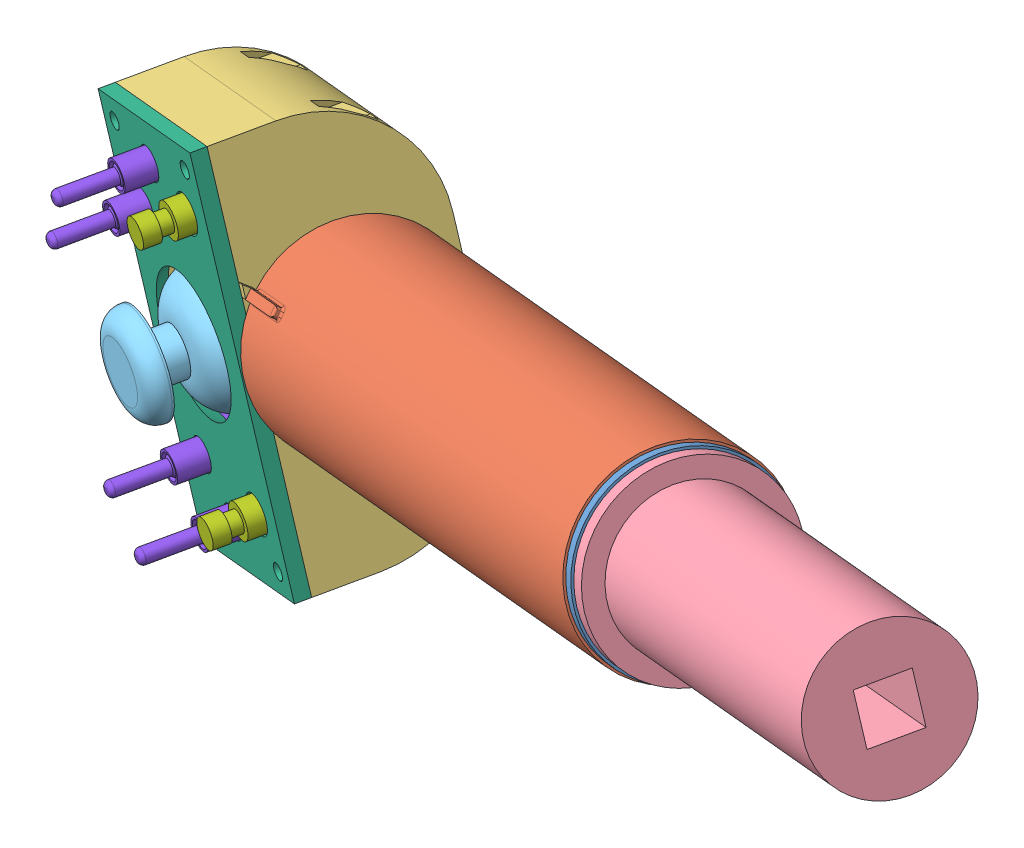
SolidWorks assembly simple_collective_body, configuration По умолчанию. Lengths in mm.
Overall size (251.38 127.81 120.21).
12 component instances, 8 part files, 32 mates.
Components (placement in the parent):
- simple_collective_throttle_frame_part1_slbody02-1: simple_collective_throttle_frame_part1_slbody02 [По умолчанию] at (-143.9465 367.1598 155.02) x (0.322697 0.099734 -0.941233) z (0.295284 -0.95541 0) size (39 92 39)
- simple_collective_throttle_grip_slbody04-1: simple_collective_throttle_grip_slbody04 [По умолчанию] at (-94.487 382.4459 173.5966) x (-0.221382 -0.376779 0.89946) z (-0.899263 -0.277931 -0.337757) size (40 40 126.4)
- simple_collective_throttle_frame_part2_slbody03a-1: simple_collective_throttle_frame_part2_slbody03a [По умолчанию] at (-157.4354 362.9908 149.9536) x (0.295284 -0.95541 0) z (-0.899263 -0.277931 -0.337757) size (78 41.6 93)
- simple_lever_body_decorative_casing_slbody01-2: simple_lever_body_decorative_casing_slbody01 [По умолчанию] at (-20.7474 405.2363 201.2927) x (0.322697 0.099734 -0.941233) z (-0.295284 0.95541 0) size (38 80 38)
- KY-083-2: KY-083 [По умолчанию] at (-223.9465 342.4345 123.3789) x (0.899263 0.277931 0.337757) z (0.295284 -0.95541 0) size (27.6 34.3 38.4)
- compact_collective_switchbox_cover_slbody05-1: compact_collective_switchbox_cover_slbody05 [По умолчанию] at (-230.366 340.4505 140.6228) x (-0.295284 0.95541 0) z (0.899263 0.277931 0.337757) size (78 3 37.5)
- PBS10-B2-1: PBS10-B2 [По умолчанию] at (-226.4692 368.8683 136.4705) x (0.884331 0.322697 0.337381) z (0.337381 -0.941233 0.015935) size (9.4 20 9.4)
- MTS-103-1: MTS-103 [По умолчанию] at (-238.2527 370.4598 131.0056) x (0.899263 0.277931 0.337757) z (0.295284 -0.95541 0) size (13.2 33.3 7.9)
- MTS-103-4: MTS-103 [По умолчанию] at (-219.9452 311.2244 131.0056) x (0.899263 0.277931 0.337757) z (0.295284 -0.95541 0) size (13.2 33.3 7.9)
- MTS-103-5: MTS-103 [По умолчанию] at (-229.0452 318.3553 128.6413) x (0.899263 0.277931 0.337757) z (0.295284 -0.95541 0) size (13.2 33.3 7.9)
- MTS-103-6: MTS-103 [По умолчанию] at (-241.7424 359.4379 128.6413) x (0.899263 0.277931 0.337757) z (0.295284 -0.95541 0) size (13.2 33.3 7.9)
- PBS10-B2-2: PBS10-B2 [По умолчанию] at (-211.1145 319.187 136.4705) x (0.884331 0.322697 0.337381) z (0.337381 -0.941233 0.015935) size (9.4 20 9.4)
Mates (geometry in assembly coordinates):
- Coincident58: coincident anti-aligned: plane of simple_collective_throttle_frame_part1_slbody02-1 through (-94.487 382.4459 173.5966) normal (-0.899263 -0.277931 -0.337757); plane of simple_collective_throttle_grip_slbody04-1 through (-94.487 382.4459 173.5966) normal (0.899263 0.277931 0.337757)
- Concentric21: concentric anti-aligned: cylinder of simple_collective_throttle_frame_part1_slbody02-1 through (-94.487 382.4459 173.5966) axis (-0.899263 -0.277931 -0.337757) radius 18; cylinder of simple_collective_throttle_grip_slbody04-1 through (-208.1539 347.3155 130.9041) axis (0.899263 0.277931 0.337757) radius 18.5
- Concentric27: concentric anti-aligned: cylinder of simple_collective_throttle_frame_part1_slbody02-1 through (-94.487 382.4459 173.5966) axis (-0.899263 -0.277931 -0.337757) radius 18; cylinder of simple_collective_throttle_frame_part2_slbody03a-1 through (-208.6935 347.1487 130.7015) axis (0.899263 0.277931 0.337757) radius 18
- Parallel4: parallel anti-aligned: plane of simple_collective_throttle_frame_part1_slbody02-1 through (-169.3547 355.5106 128.6293) normal (0.322697 0.099734 -0.941233); plane of simple_collective_throttle_frame_part2_slbody03a-1 through (-172.3663 364.18 128.3294) normal (-0.322697 -0.099734 0.941233)
- Coincident60: coincident anti-aligned: plane of simple_collective_throttle_frame_part1_slbody02-1 through (-157.4354 362.9908 149.9536) normal (-0.899263 -0.277931 -0.337757); plane of simple_collective_throttle_frame_part2_slbody03a-1 through (-157.4354 362.9908 149.9536) normal (0.899263 0.277931 0.337757)
- Concentric28: concentric anti-aligned: cylinder of simple_collective_throttle_frame_part1_slbody02-1 through (-92.6885 383.0018 174.2722) axis (-0.899263 -0.277931 -0.337757) radius 19.5; cylinder of simple_lever_body_decorative_casing_slbody01-2 through (-92.6885 383.0018 174.2722) axis (0.899263 0.277931 0.337757) radius 15
- Parallel5: parallel aligned: plane of simple_collective_throttle_frame_part1_slbody02-1 through (-131.8262 376.2699 165.5857) normal (0.295284 -0.95541 0); plane of simple_lever_body_decorative_casing_slbody01-2 through (-92.5473 388.4358 169.4248) normal (0.295284 -0.95541 0)
- Coincident62: coincident anti-aligned: plane of simple_collective_throttle_frame_part1_slbody02-1 through (-92.6885 383.0018 174.2722) normal (0.899263 0.277931 0.337757); plane of simple_lever_body_decorative_casing_slbody01-2 through (-92.6885 383.0018 174.2722) normal (-0.899263 -0.277931 -0.337757)
- Coincident66: coincident anti-aligned: plane of simple_collective_throttle_frame_part2_slbody03a-1 through (-235.0367 298.1868 134.5432) normal (-0.322697 -0.099734 0.941233); plane of compact_collective_switchbox_cover_slbody05-1 through (-230.366 340.4505 140.6228) normal (0.322697 0.099734 -0.941233)
- Coincident67: coincident aligned: plane of simple_collective_throttle_frame_part2_slbody03a-1 through (-208.6935 347.1487 130.7015) normal (0.899263 0.277931 0.337757); plane of compact_collective_switchbox_cover_slbody05-1 through (-226.6635 382.415 149.5261) normal (0.899263 0.277931 0.337757)
- Coincident68: coincident aligned: plane of simple_collective_throttle_frame_part2_slbody03a-1 through (-258.0688 372.7087 134.5432) normal (-0.295284 0.95541 0); plane of compact_collective_switchbox_cover_slbody05-1 through (-226.6635 382.415 149.5261) normal (-0.295284 0.95541 0)
- Parallel10: parallel anti-aligned: plane of simple_collective_throttle_frame_part2_slbody03a-1 through (-196.1147 313.3562 27.3146) normal (0.899263 0.277931 0.337757); plane of KY-083-2 through (-232.1351 322.372 122.1641) normal (-0.899263 -0.277931 -0.337757)
- Distance2: distance = 15 mm anti-aligned: plane of KY-083-2 through (-225.076 342.0855 126.6732) normal (-0.322697 -0.099734 0.941233); plane of compact_collective_switchbox_cover_slbody05-1 through (-230.366 340.4505 140.6228) normal (0.322697 0.099734 -0.941233)
- Concentric38: concentric anti-aligned: cylinder of simple_collective_throttle_frame_part2_slbody03a-1 through (-213.5155 361.2015 108.4386) axis (-0.322697 -0.099734 0.941233) radius 1.5; cylinder of KY-083-2 through (-230.8123 355.8556 158.8897) axis (0.322697 0.099734 -0.941233) radius 1.45
- Concentric39: concentric anti-aligned: cylinder of simple_collective_throttle_frame_part2_slbody03a-1 through (-224.273 330.6633 101.5146) axis (-0.322697 -0.099734 0.941233) radius 1.5; cylinder of KY-083-2 through (-241.5699 325.3174 151.9657) axis (0.322697 0.099734 -0.941233) radius 1.45
- Concentric40: concentric anti-aligned: cylinder of compact_collective_switchbox_cover_slbody05-1 through (-230.0189 367.7713 146.8241) axis (0.322697 0.099734 -0.941233) radius 3.75; cylinder of PBS10-B2-1 through (-229.0508 368.0705 144.0004) axis (-0.322697 -0.099734 0.941233) radius 3.4
- Coincident81: coincident anti-aligned: plane of compact_collective_switchbox_cover_slbody05-1 through (-230.366 340.4505 140.6228) normal (0.322697 0.099734 -0.941233); plane of PBS10-B2-1 through (-229.0508 368.0705 144.0004) normal (-0.322697 -0.099734 0.941233)
- Coincident93: coincident aligned: plane of simple_collective_throttle_grip_slbody04-1 through (-207.6279 361.1244 150.7085) normal (0.018775 -0.795994 0.605013); plane of simple_collective_throttle_frame_part2_slbody03a-1 through (-216.197 357.6854 146.45) normal (0.018775 -0.795994 0.605013)
- Coincident97: coincident anti-aligned: plane of compact_collective_switchbox_cover_slbody05-1 through (-230.366 340.4505 140.6228) normal (0.322697 0.099734 -0.941233); plane of MTS-103-4 through (-223.0108 310.2769 139.9473) normal (-0.322697 -0.099734 0.941233)
- Coincident100: coincident anti-aligned: plane of compact_collective_switchbox_cover_slbody05-1 through (-230.366 340.4505 140.6228) normal (0.322697 0.099734 -0.941233); plane of MTS-103-1 through (-241.3184 369.5123 139.9473) normal (-0.322697 -0.099734 0.941233)
- Parallel18: parallel: line of compact_collective_switchbox_cover_slbody05-1 through (-235.0367 298.1868 134.5432) axis (0.899263 0.277931 0.337757); plane of MTS-103-4 through (-215.9093 308.3374 142.1765) normal (0.295284 -0.95541 0)
- Parallel20: parallel aligned: plane of compact_collective_switchbox_cover_slbody05-1 through (-226.6635 382.415 149.5261) normal (-0.295284 0.95541 0); plane of MTS-103-1 through (-236.5496 375.1205 142.1765) normal (-0.295284 0.95541 0)
- Concentric43: concentric aligned: cylinder of compact_collective_switchbox_cover_slbody05-1 through (-223.9789 309.9777 142.771) axis (0.322697 0.099734 -0.941233) radius 3.2; cylinder of MTS-103-4 through (-225.8505 309.3993 148.2301) axis (0.322697 0.099734 -0.941233) radius 3
- Concentric44: concentric aligned: cylinder of compact_collective_switchbox_cover_slbody05-1 through (-242.2864 369.2131 142.771) axis (0.322697 0.099734 -0.941233) radius 3.2; cylinder of MTS-103-1 through (-244.1581 368.6347 148.2301) axis (0.322697 0.099734 -0.941233) radius 3
- Concentric45: concentric aligned: cylinder of compact_collective_switchbox_cover_slbody05-1 through (-233.0789 317.1086 140.4067) axis (0.322697 0.099734 -0.941233) radius 3.2; cylinder of MTS-103-5 through (-234.9505 316.5302 145.8658) axis (0.322697 0.099734 -0.941233) radius 3
- Concentric46: concentric aligned: cylinder of compact_collective_switchbox_cover_slbody05-1 through (-245.7761 358.1912 140.4067) axis (0.322697 0.099734 -0.941233) radius 3.2; cylinder of MTS-103-6 through (-247.6477 357.6128 145.8658) axis (0.322697 0.099734 -0.941233) radius 3
- Coincident101: coincident anti-aligned: plane of compact_collective_switchbox_cover_slbody05-1 through (-230.366 340.4505 140.6228) normal (0.322697 0.099734 -0.941233); plane of MTS-103-5 through (-232.1108 317.4078 137.583) normal (-0.322697 -0.099734 0.941233)
- Coincident102: coincident anti-aligned: plane of compact_collective_switchbox_cover_slbody05-1 through (-230.366 340.4505 140.6228) normal (0.322697 0.099734 -0.941233); plane of MTS-103-6 through (-244.808 358.4904 137.583) normal (-0.322697 -0.099734 0.941233)
- Parallel21: parallel anti-aligned: plane of MTS-103-4 through (-218.242 315.8851 142.1765) normal (-0.295284 0.95541 0); plane of MTS-103-5 through (-225.0093 315.4683 139.8122) normal (0.295284 -0.95541 0)
- Parallel22: parallel anti-aligned: plane of MTS-103-1 through (-234.2169 367.5728 142.1765) normal (0.295284 -0.95541 0); plane of MTS-103-6 through (-240.0392 364.0986 139.8122) normal (-0.295284 0.95541 0)
- Concentric47: concentric anti-aligned: cylinder of compact_collective_switchbox_cover_slbody05-1 through (-214.6641 318.09 146.8241) axis (0.322697 0.099734 -0.941233) radius 3.75; cylinder of PBS10-B2-2 through (-213.696 318.3892 144.0004) axis (-0.322697 -0.099734 0.941233) radius 3.4
- Coincident105: coincident anti-aligned: plane of compact_collective_switchbox_cover_slbody05-1 through (-230.366 340.4505 140.6228) normal (0.322697 0.099734 -0.941233); plane of PBS10-B2-2 through (-213.696 318.3892 144.0004) normal (-0.322697 -0.099734 0.941233)
